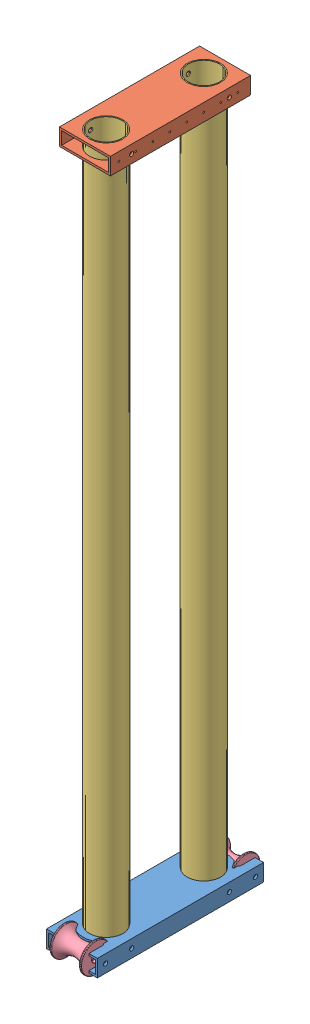
SolidWorks assembly 23-000 Third Stage Asm, configuration Default. Lengths in mm.
Overall size (76.2 1070.09 281.42).
6 component instances, 4 part files, 17 mates.
Components (placement in the parent):
- 230-001 third stage base-1: 230-001 third stage base [Default] at (-22.5646 99.9679 -130.9982) size (76.2 25.4 248.48)
- 230-003 third stage top-1: 230-003 third stage top [Default] at (-22.5646 1128.6679 -96.0732) size (76.2 25.4 209.55)
- 230-002 Third Stage Rod-1: 230-002 Third Stage Rod [Default] at (-22.5646 87.2679 -64.3232) x (-1 0 0) z (0 0 -1) size (49.94 1054.1 49.94)
- 230-002 Third Stage Rod-2: 230-002 Third Stage Rod [Default] at (-22.5646 87.2679 81.7268) x (-1 0 0) z (0 0 -1) size (49.94 1054.1 49.94)
- 200-001 Roller 3-1: 200-001 Roller 3 [Default] at (-22.5646 99.9679 -103.3122) x (0 0.381849 -0.924225) z (0 -0.924225 -0.381849) size (43.94 46.98 43.94)
- 200-001 Roller 3-2: 200-001 Roller 3 [Default] at (-22.5646 99.9679 120.7158) x (0 0.381849 -0.924225) z (0 -0.924225 -0.381849) size (43.94 46.98 43.94)
Mates (geometry in assembly coordinates):
- Coincident1: coincident: plane of 230-001 third stage base-1 through (-60.6646 87.2679 148.4018) normal (0 -1 0); plane of 230-002 Third Stage Rod-2 through (-22.5646 87.2679 81.7268) normal (0 -1 0)
- Coincident2: coincident: plane of 230-001 third stage base-1 through (-60.6646 87.2679 148.4018) normal (0 -1 0); plane of 230-002 Third Stage Rod-1 through (-22.5646 87.2679 -64.3232) normal (0 -1 0)
- Coincident3: coincident: plane of 230-003 third stage top-1 through (-60.6646 1141.3679 113.4768) normal (0 1 0); plane of 230-002 Third Stage Rod-1 through (-22.5646 1141.3679 -64.3232) normal (0 1 0)
- Concentric1: concentric: circle of 230-001 third stage base-1; circle of ?
- Concentric2: concentric: circle of 230-001 third stage base-1; circle of ?
- Concentric3: concentric: cylinder of 230-001 third stage base-1 through (-22.5646 87.2679 -64.3232) axis (0 1 0) radius 24.972; cylinder of 230-002 Third Stage Rod-1 through (-22.5646 1141.3679 -64.3232) axis (0 -1 0) radius 24.972
- Concentric4: concentric: cylinder of 230-001 third stage base-1 through (-22.5646 87.2679 81.7268) axis (0 1 0) radius 24.972; cylinder of 230-002 Third Stage Rod-2 through (-22.5646 1141.3679 81.7268) axis (0 -1 0) radius 24.972
- Width1: width: plane of ? through (-40.2176 99.9679 120.7158) normal (-1 0 0); plane of ? through (-4.9116 99.9679 120.7158) normal (1 0 0); plane of 230-001 third stage base-1 through (-45.4246 99.9679 148.4018) normal (1 0 0); plane of 230-001 third stage base-1 through (0.2954 99.9679 148.4018) normal (-1 0 0)
- Width2: width: plane of ? through (-40.2176 99.9679 -103.3122) normal (-1 0 0); plane of ? through (-4.9116 99.9679 -103.3122) normal (1 0 0); plane of 230-001 third stage base-1 through (-45.4246 99.9679 148.4018) normal (1 0 0); plane of 230-001 third stage base-1 through (0.2954 99.9679 148.4018) normal (-1 0 0)
- Concentric5: concentric: cylinder of 230-003 third stage top-1 through (-22.5646 1115.9679 -64.3232) axis (0 1 0) radius 24.972; cylinder of 230-002 Third Stage Rod-1 through (-22.5646 1141.3679 -64.3232) axis (0 -1 0) radius 24.972
- Concentric6: concentric: cylinder of 230-003 third stage top-1 through (-22.5646 1115.9679 81.7268) axis (0 1 0) radius 24.972; cylinder of 230-002 Third Stage Rod-2 through (-22.5646 1141.3679 81.7268) axis (0 -1 0) radius 24.972
- Concentric7: concentric: cylinder of 230-003 third stage top-1 through (-60.6646 1128.6679 -64.3232) axis (1 0 0) radius 3.175; cylinder of 230-002 Third Stage Rod-1 through (2.4074 1128.6679 -64.3232) axis (-1 0 0) radius 3.175
- Concentric8: concentric: cylinder of 230-003 third stage top-1 through (-60.6646 1128.6679 81.7268) axis (1 0 0) radius 3.175; cylinder of 230-002 Third Stage Rod-2 through (2.4074 1128.6679 81.7268) axis (-1 0 0) radius 3.175
- Concentric9: concentric: cylinder of 230-001 third stage base-1 through (-60.6646 99.9679 120.7158) axis (1 0 0) radius 3.175; cylinder of 200-001 Roller 3-2 through (0.9256 99.9679 120.7158) axis (1 0 0) radius 6.35
- Width3: width: plane of 200-001 Roller 3-2 through (0.9256 99.9679 120.7158) normal (1 0 0); plane of 200-001 Roller 3-2 through (-46.0549 99.9679 120.7158) normal (-1 0 0); plane of 230-001 third stage base-1 through (-57.4896 99.9679 148.4018) normal (1 0 0); plane of 230-001 third stage base-1 through (12.3604 99.9679 148.4018) normal (-1 0 0)
- Concentric10: concentric: cylinder of 230-001 third stage base-1 through (-60.6646 99.9679 -103.3122) axis (1 0 0) radius 3.175; cylinder of 200-001 Roller 3-1 through (0.9256 99.9679 -103.3122) axis (1 0 0) radius 6.35
- Coincident4: coincident: plane of 200-001 Roller 3-1 through (0.9256 99.9679 -103.3122) normal (1 0 0); plane of 200-001 Roller 3-2 through (0.9256 99.9679 120.7158) normal (1 0 0)
